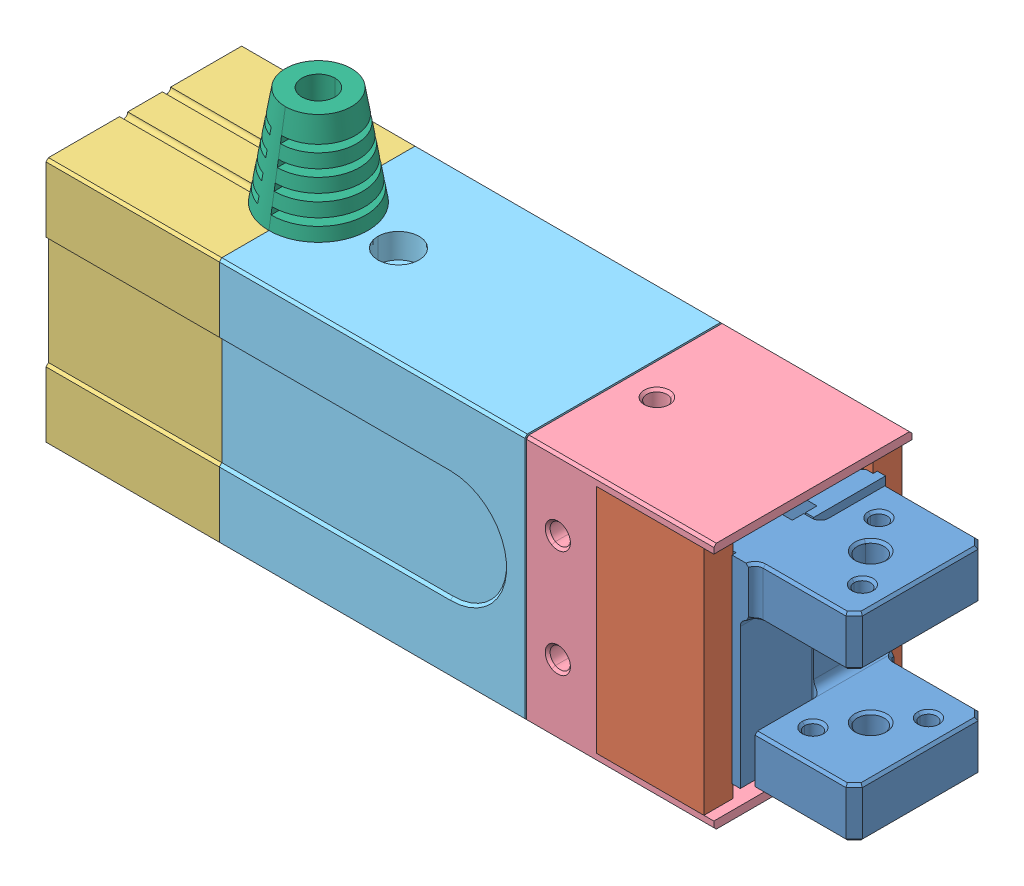
SolidWorks assembly 3D图, configuration 默认. Lengths in mm.
Overall size (93.9 42.01 24).
12 component instances, 6 part files, 0 mates.
Components (placement in the parent):
- 3D图.stp-1: 3D图.stp [默认] at origin size (93.9 42.01 24)
  - Z-100-0002-00.stp-1: Z-100-0002-00.stp [默认] at (-79.9268 -84.8342 -7.192) size (28.2 28 24)
    - 1000010000503.stp-1: 1000010000503.stp [默认] at (203.4615 84.6423 7.5832) x (-1 0 0) z (0 0 1) size (23.1 24 16.81)
    - 1000010000402.stp-1: 1000010000402.stp [默认] at (207.3115 84.8342 7.4832) x (-1 0 0) z (0 0 1) size (14 28 24)
    - 1000010000503.stp-2: 1000010000503.stp [默认] at (203.4615 84.6423 7.3832) x (-1 0 0) z (0 0 -1) size (23.1 24 16.81)
  - Z-100-0003-01.stp-1: Z-100-0003-01.stp [默认] at (58.1848 -5.375 -23.6605) x (0 0 -1) z (-1 0 0) size (24 30 22)
    - 1000013000103.stp-1: 1000013000103.stp [默认] at (-23.9517 -5.375 10.5) x (-1 0 0) z (0 0 -1) size (24 30 22)
  - Z-100-0007-00.stp-1: Z-100-0007-00.stp [默认] at (0.3 0 0.2912) size (23.9 30 24)
    - 1000010000301.stp-1: 1000010000301.stp [默认] at (104.3848 0 0) x (0 1 0) z (1 0 0) size (30 24 23.9)
  - Z-100-0001-01.stp-1: Z-100-0001-01.stp [默认] at origin size (43 42.01 24)
    - 101-100-0002-03.stp-1: 101-100-0002-03.stp [默认] at (68.6848 0 0.2912) x (1 0 0) z (0 0 -1) size (37 30 24)
    - WEIGUAN.stp-1: WEIGUAN.stp [默认] at (68.6848 15 0.2912) x (0 1 0) z (0 0 1) size (14.51 12 12.04)
